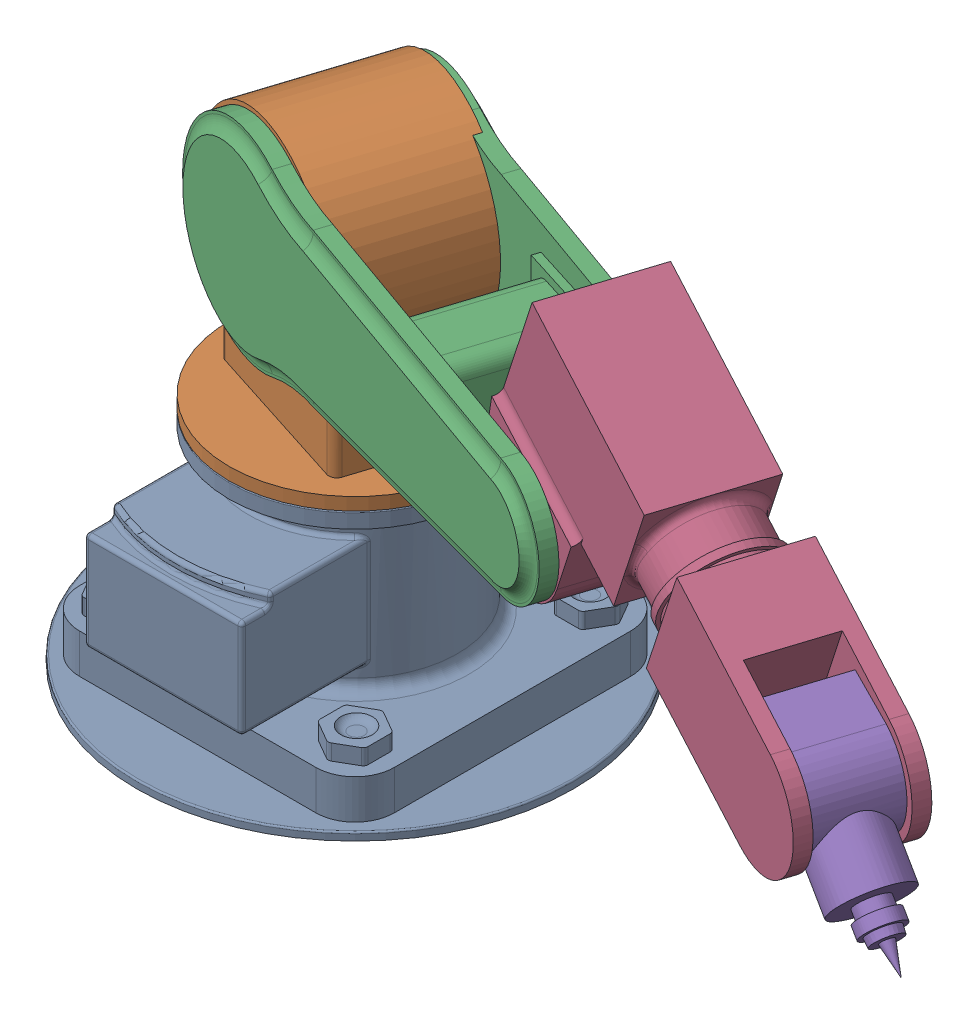
SolidWorks assembly Industrial Design Phase 2 Assignment, configuration Default. Lengths in mm.
Overall size (1368.38 738.51 680.4).
5 component instances, 5 part files, 8 mates.
Components (placement in the parent):
- base 1-1: base 1 [Default] at (-94.8166 -157.8785 62.1798) size (555 280 555)
- base 2-1: base 2 [Default] at (-94.8166 2.1215 62.1798) x (-0.952291 0 -0.305192) z (0.305192 0 -0.952291) size (320 466 320)
- link 2-1: link 2 [Default] at (-96.3425 338.1215 66.9412) x (-0.007341 0.99997 -0.002353) z (-0.952263 -0.007709 -0.305183) size (250 232.14 700)
- link 3-1: link 3 [Default] at (352.544 511.8651 216.0516) x (0.873187 -0.399042 0.27984) z (-0.305192 0 0.952291) size (585 297.5 160)
- link 4-1: link 4 [Default] at (797.8692 308.3537 358.7702) x (0.737134 -0.633108 0.236238) z (-0.305192 0 0.952291) size (275 130 100)
Mates (geometry in assembly coordinates):
- Concentric1: concentric anti-aligned: cylinder of base 1-1 through (-94.8166 -77.8785 62.1798) axis (0 1 0) radius 100; cylinder of base 2-1 through (-94.8166 122.1215 62.1798) axis (0 -1 0) radius 100
- Coincident1: coincident aligned: plane of base 1-1 through (-94.8166 122.1215 62.1798) normal (0 1 0); circle of base 2-1
- Concentric2: concentric aligned: cylinder of base 2-1 through (-67.3493 338.1215 -23.5264) axis (-0.305192 0 0.952291) radius 75; cylinder of link 2-1 through (-67.3493 338.1215 -23.5264) axis (-0.305192 0 0.952291) radius 75
- Coincident2: coincident anti-aligned: plane of base 2-1 through (-122.2838 338.1215 147.886) normal (-0.305192 0 0.952291); plane of link 2-1 through (-122.2838 338.1215 147.886) normal (0.305192 0 -0.952291)
- Concentric3: concentric anti-aligned: cylinder of link 2-1 through (408.782 341.9758 129.0649) axis (-0.305192 0 0.952291) radius 50; cylinder of link 3-1 through (353.8475 341.9758 300.4773) axis (0.305192 0 -0.952291) radius 50
- Coincident3: coincident anti-aligned: plane of link 2-1 through (-122.2838 338.1215 147.886) normal (0.305192 0 -0.952291); plane of link 3-1 through (328.1287 511.8651 292.2349) normal (-0.305192 0 0.952291)
- Concentric4: concentric aligned: cylinder of link 3-1 through (782.6096 308.3537 406.3847) axis (0.305192 0 -0.952291) radius 50; cylinder of link 4-1 through (782.6096 308.3537 406.3847) axis (0.305192 0 -0.952291) radius 50
- Coincident5: coincident aligned: circle of link 3-1; plane of link 4-1 through (782.6096 308.3537 406.3847) normal (-0.305192 0 0.952291)
